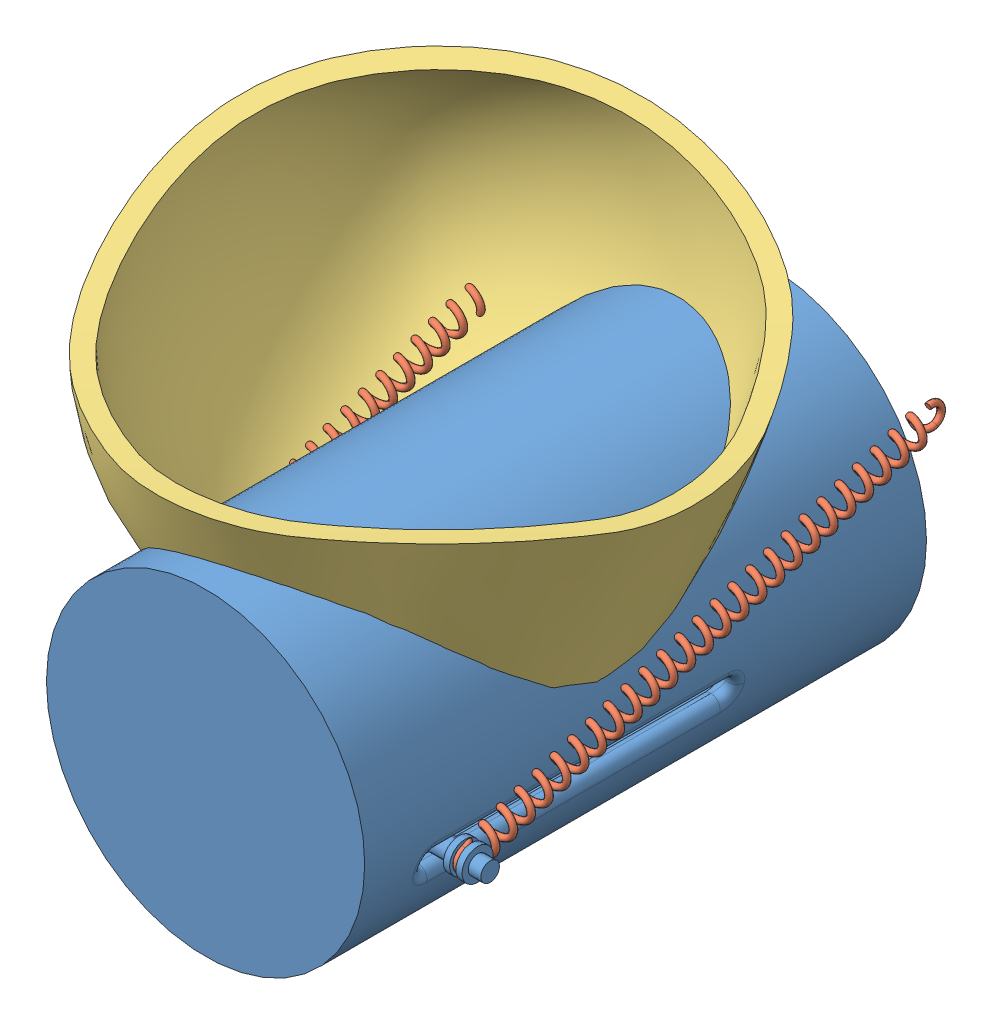
SolidWorks assembly assembly spring to cylinder, configuration Default. Lengths in mm.
Overall size (129.69 86.84 130.19).
4 component instances, 3 part files, 3 mates.
Components (placement in the parent):
- bottom part-1: bottom part [Default] at (17.6442 59.2949 24.1241) size (62 51 90)
- spring-1: spring [Default] at (-10.7255 80.6299 27.7939) x (0 -0.936629 -0.350322) z (-1 0 0) size (5.47 82.4 5.47)
- spring-2: spring [Default] at (44.9754 77.586 26.7279) x (0 -0.950546 -0.310585) z (-1 0 0) size (5.47 82.4 5.47)
- funnel_1-1: funnel_1 [Default] at (13.6291 112.2131 71.8439) x (-0.727112 -0.084636 -0.681282) z (-0.684228 0.008331 0.729221) size (88.22 55.15 91.27)
Mates (geometry in assembly coordinates):
- Concentric1: concentric: cylinder of bottom part-1 through (-13.3558 53.7952 99.5397) axis (1 0 0) radius 1.5; circle of spring-1
- Concentric3: concentric: cylinder of bottom part-1 through (-13.3558 53.7952 99.5397) axis (1 0 0) radius 1.5; circle of spring-1
- Concentric5: concentric: cylinder of bottom part-1 through (-13.3558 53.7952 99.5397) axis (1 0 0) radius 1.5; circle of spring-2
